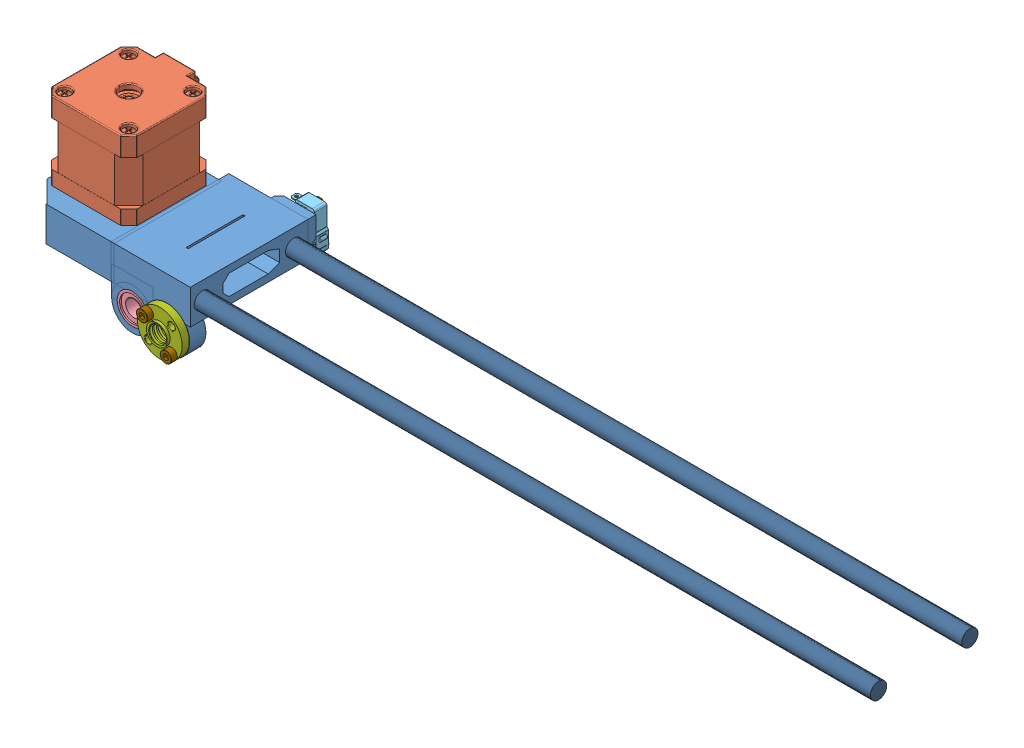
SolidWorks assembly Assembly x-axis, configuration Valor predeterminado. Lengths in mm.
Overall size (414.51 77.47 77.9).
19 component instances, 10 part files, 4 mates.
Components (placement in the parent):
- Assembly x-axis left-1: Assembly x-axis left [Valor predeterminado] at (24.9592 -12.1217 116.5135) size (85.56 77.47 77.9)
  - x-end-motor-1: x-end-motor [Valor predeterminado] at (-28.5 -15 0) x (0 -1 0) z (0 0 -1) size (34.73 81.5 62)
  - Stepper motor Nema 17-1: Stepper motor Nema 17 [Valor predeterminado] at (-36.3722 21 -25.9956) x (0 1 0) z (0 0 -1) size (62.01 42.01 48.01)
  - Screw DIN 912 - M3 x 20 --- 20N-1: Screw DIN 912 - M3 x 20 --- 20N [Valor predeterminado] at (-76 -10 -14.75) x (0 -1 0) z (-0.89717 0 -0.441685) size (23 5.5 5.5)
  - Screw DIN 912 - M3 x 20 --- 20N-2: Screw DIN 912 - M3 x 20 --- 20N [Valor predeterminado] at (-45 -10 -14.75) x (0 -1 0) z (-0.89717 0 -0.441685) size (23 5.5 5.5)
  - Screw DIN 912 - M3 x 20 --- 20N-3: Screw DIN 912 - M3 x 20 --- 20N [Valor predeterminado] at (-45 -10 -45.75) x (0 -1 0) z (-0.89717 0 -0.441685) size (23 5.5 5.5)
  - Linear bearing LM8UU-1: Linear bearing LM8UU [Valor predeterminado] at (-36.5476 -6.4908 -17.5556) x (0 0 -1) z (0.968493 0.249041 0) size (24 15 15)
  - Linear bearing LM8UU-2: Linear bearing LM8UU [Valor predeterminado] at (-36.5476 -6.4908 -51.5556) x (0 0 -1) z (0.968493 0.249041 0) size (24 15 15)
  - Microswitch without leaver - KW11-3Z 5A 250VAC-1: Microswitch without leaver - KW11-3Z 5A 250VAC [Valor predeterminado] at (-5.2875 -0.1625 -65.2) x (0 1 0) z (0 0 -1) size (19.85 15.2 6.4)
  - Pulley GT2 20T-1: Pulley GT2 20T [Valor predeterminado] at (-60.5 -10.95 -30.25) x (0 1 0) z (0.980611 0 -0.195965) size (16 16 16)
  - LeadScrew Nut - 8 x 2-1: LeadScrew Nut - 8 x 2 [Default] at (-11.5 -15 3.5) x (0.707107 0.707107 0) z (0 0 1) size (22 22 16.05)
  - Nut DIN 934 - M3-1: Nut DIN 934 - M3 [Valor predeterminado] at (-5.631 -20.869 -7.2) x (0 0 -1) z (0.707107 0.707107 0) size (2.4 5.5 6.35)
  - Nut DIN 934 - M3-2: Nut DIN 934 - M3 [Valor predeterminado] at (-17.369 -9.131 -7.2) x (0 0 -1) z (0.258819 0.965926 0) size (2.4 5.5 6.35)
  - Screw DIN 912 - M3 x 12 --- 12N-1: Screw DIN 912 - M3 x 12 --- 12N [Valor predeterminado] at (-5.631 -20.869 6.5) x (0 0 1) z (-0.933618 0.358271 0) size (15 5.5 5.5)
  - Screw DIN 912 - M3 x 12 --- 12N-2: Screw DIN 912 - M3 x 12 --- 12N [Valor predeterminado] at (-17.369 -9.131 6.5) x (0 0 1) z (-0.253715 0.967279 0) size (15 5.5 5.5)
  - Screw DIN 912 - M3 x 12 --- 12N-3: Screw DIN 912 - M3 x 12 --- 12N [Valor predeterminado] at (-7.5 4.775 -71.4) x (0 0 -1) z (0.333183 0.942862 0) size (15 5.5 5.5)
  - Screw DIN 912 - M3 x 12 --- 12N-4: Screw DIN 912 - M3 x 12 --- 12N [Valor predeterminado] at (-7.5 -4.75 -71.4) x (0 0 -1) z (0.744402 0.667732 0) size (15 5.5 5.5)
- Smooth Rod - 8 x 370-1: Smooth Rod - 8 x 370 [Valor predeterminado] at (172.9592 -12.1217 110.5135) x (0 0.46876 0.883326) z (-1 0 0) size (8 8 370)
- Smooth Rod - 8 x 370-2: Smooth Rod - 8 x 370 [Valor predeterminado] at (172.9592 -12.1217 65.5135) x (0 0.921342 0.388752) z (-1 0 0) size (8 8 370)
Mates (geometry in assembly coordinates):
- Concêntrico1: concentric: cylinder of assembly; cylinder of assembly; cylinder of Assembly x-axis left-1/x-end-motor-1 through (37.9592 -12.1217 110.5135) axis (-1 0 0) radius 4.0764; cylinder of Smooth Rod - 8 x 370-1 through (-12.0408 -12.1217 110.5135) axis (1 0 0) radius 4
- Coincidente1: coincident: plane of assembly; plane of assembly; plane of Assembly x-axis left-1/x-end-motor-1 through (-12.0408 -12.1217 110.5135) normal (1 0 0); plane of Smooth Rod - 8 x 370-1 through (-12.0408 -12.1217 110.5135) normal (-1 0 0)
- Concêntrico3: concentric: cylinder of assembly; cylinder of assembly; cylinder of Assembly x-axis left-1/x-end-motor-1 through (37.9592 -12.1217 65.5135) axis (-1 0 0) radius 4.0764; cylinder of Smooth Rod - 8 x 370-2 through (-12.0408 -12.1217 65.5135) axis (1 0 0) radius 4
- Coincidente3: coincident: plane of assembly; plane of assembly; plane of Assembly x-axis left-1/x-end-motor-1 through (-12.0408 -12.1217 65.5135) normal (1 0 0); plane of Smooth Rod - 8 x 370-2 through (-12.0408 -12.1217 65.5135) normal (-1 0 0)
